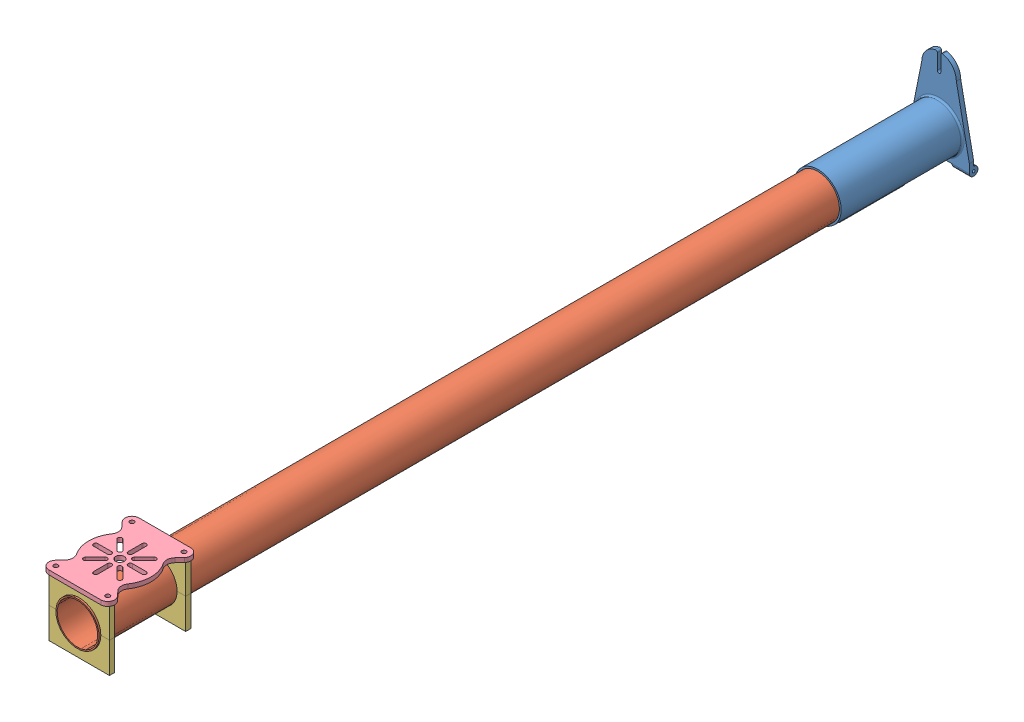
SolidWorks assembly 50mmArmAssembly, configuration Default. Lengths in mm.
Overall size (76 110.85 1008).
7 component instances, 4 part files, 11 mates.
Components (placement in the parent):
- 50mmHingeToArm-1: 50mmHingeToArm [Default] at (113.0694 125.4328 79.3641) size (70 110.85 150)
- 50mmDiamDroneArm-1: 50mmDiamDroneArm [Default] at (113.0694 125.4328 79.3641) x (0.775778 0.631006 0) z (0 0 1) size (50 50 995)
- 50mmTubeClamp-1: 50mmTubeClamp [Default] at (113.0694 125.4328 1064.3641) size (70 35.35 6)
- 50mmTubeClamp-2: 50mmTubeClamp [Default] at (113.0694 125.4328 1064.3641) x (-1 0 0) z (0 0 1) size (70 35.35 6)
- 50mmTubeClamp-3: 50mmTubeClamp [Default] at (113.0694 125.4328 976.3641) x (-1 0 0) z (0 0 1) size (70 35.35 6)
- 50mmTubeClamp-4: 50mmTubeClamp [Default] at (113.0694 125.4328 976.3641) size (70 35.35 6)
- 50mmMotorHolder-1: 50mmMotorHolder [Default] at (104.7598 160.7795 1001.9104) size (76 5 104)
Mates (geometry in assembly coordinates):
- Concentric2: concentric aligned: cylinder of 50mmHingeToArm-1 through (113.0694 125.4328 219.3641) axis (0 0 -1) radius 25; cylinder of 50mmDiamDroneArm-1 through (113.0694 125.4328 1074.3641) axis (0 0 -1) radius 25
- Coincident2: coincident anti-aligned: plane of 50mmHingeToArm-1 through (113.0694 180.4328 79.3641) normal (0 0 1); plane of 50mmDiamDroneArm-1 through (113.0694 125.4328 79.3641) normal (0 0 -1)
- Coincident3: coincident anti-aligned: plane of 50mmTubeClamp-1 through (148.0694 125.4328 1074.3641) normal (0 -1 0); plane of 50mmTubeClamp-2 through (78.0694 125.4328 1074.3641) normal (0 1 0)
- Concentric3: concentric aligned: cylinder of 50mmDiamDroneArm-1 through (113.0694 125.4328 1074.3641) axis (0 0 -1) radius 25; cylinder of 50mmTubeClamp-2 through (113.0694 125.4328 1074.3641) axis (0 0 -1) radius 25
- Concentric4: concentric aligned: cylinder of 50mmDiamDroneArm-1 through (113.0694 125.4328 1074.3641) axis (0 0 -1) radius 25; cylinder of 50mmTubeClamp-1 through (113.0694 125.4328 1074.3641) axis (0 0 -1) radius 25
- Coincident7: coincident anti-aligned: plane of 50mmTubeClamp-3 through (138.0694 125.4328 986.3641) normal (0 1 0); plane of 50mmTubeClamp-4 through (88.0694 125.4328 986.3641) normal (0 -1 0)
- Concentric5: concentric aligned: cylinder of 50mmDiamDroneArm-1 through (113.0694 125.4328 1074.3641) axis (0 0 -1) radius 25; cylinder of 50mmTubeClamp-4 through (113.0694 125.4328 986.3641) axis (0 0 -1) radius 25
- Concentric6: concentric aligned: cylinder of 50mmDiamDroneArm-1 through (113.0694 125.4328 1074.3641) axis (0 0 -1) radius 25; cylinder of 50mmTubeClamp-3 through (113.0694 125.4328 986.3641) axis (0 0 -1) radius 25
- Parallel1: parallel aligned: plane of 50mmHingeToArm-1 through (115.5694 89.131 219.3641) normal (0 -1 0); plane of 50mmTubeClamp-2 through (78.0694 90.0861 1074.3641) normal (0 -1 0)
- Parallel2: parallel aligned: plane of 50mmHingeToArm-1 through (115.5694 89.131 219.3641) normal (0 -1 0); plane of 50mmTubeClamp-3 through (78.0694 90.0861 986.3641) normal (0 -1 0)
- Coincident13: coincident anti-aligned: plane of 50mmTubeClamp-4 through (148.0694 160.7795 986.3641) normal (0 1 0); plane of 50mmMotorHolder-1 through (104.7598 160.7795 1001.9104) normal (0 -1 0)
